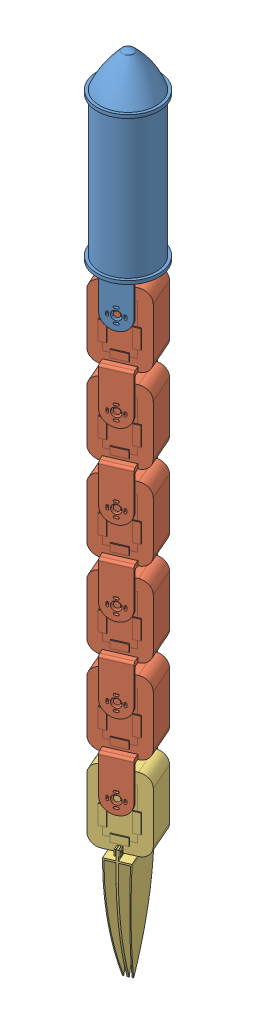
SolidWorks assembly total_final_fish, configuration 預設. Lengths in mm.
Overall size (60.87 716.27 55.2).
7 component instances, 3 part files, 19 mates.
Components (placement in the parent):
- base_link-2: base_link [預設] at (3.3602 198.1192 -73.7093) size (55 204.98 55)
- link2-6: link2 [預設] at (24.2784 37.6563 26.0615) x (0 1 0) z (0.399282 0 0.916828) size (107 45 40.5)
- link2-7: link2 [預設] at (24.2784 -37.0437 26.0615) x (0 1 0) z (0.399282 0 0.916828) size (107 45 40.5)
- link2-8: link2 [預設] at (24.2784 -111.7437 26.0615) x (0 1 0) z (0.399282 0 0.916828) size (107 45 40.5)
- link2-9: link2 [預設] at (24.2784 -186.4437 26.0615) x (0 1 0) z (0.399282 0 0.916828) size (107 45 40.5)
- link2-10: link2 [預設] at (24.2784 -261.1437 26.0615) x (0 1 0) z (0.399282 0 0.916828) size (107 45 40.5)
- link6-2: link6 [預設] at (-11.6105 -236.8157 -14.0084) x (0 1 0) z (0.399282 0 0.916828) size (170.09 49.79 38.13)
Mates (geometry in assembly coordinates):
- 同軸心9: concentric aligned: cylinder of base_link-2 through (17.4906 112.3563 10.4754) axis (-0.399282 0 -0.916828) radius 2.7; cylinder of link2-6 through (18.6885 112.3563 13.2259) axis (-0.399282 0 -0.916828) radius 2.5
- 平行2: parallel aligned: plane of base_link-2 through (5.2908 142.3563 12.5163) normal (-0.916828 0 0.399282); plane of link2-6 through (9.2398 67.6563 47.881) normal (-0.916828 0 0.399282)
- 同軸心10: concentric anti-aligned: cylinder of base_link-2 through (31.6652 112.3563 43.0228) axis (0.399282 0 0.916828) radius 4; cylinder of link2-6 through (31.8648 112.3563 43.4812) axis (-0.399282 0 -0.916828) radius 2.5
- 重合/共線/共點32: coincident aligned: plane of base_link-2 through (30.4673 112.3563 40.2724) normal (-0.399282 0 -0.916828); plane of link2-6 through (30.4673 37.6563 40.2724) normal (-0.399282 0 -0.916828)
- 重合/共線/共點33: coincident aligned: plane of link2-6 through (9.2398 67.6563 47.881) normal (-0.916828 0 0.399282); plane of link2-7 through (9.2398 -7.0437 47.881) normal (-0.916828 0 0.399282)
- 重合/共線/共點34: coincident aligned: plane of link2-6 through (30.4673 37.6563 40.2724) normal (-0.399282 0 -0.916828); plane of link2-7 through (30.4673 -37.0437 40.2724) normal (-0.399282 0 -0.916828)
- 同軸心11: concentric anti-aligned: cylinder of link2-6 through (16.2928 37.6563 7.725) axis (0.399282 0 0.916828) radius 3.7; cylinder of link2-7 through (18.6885 37.6563 13.2259) axis (-0.399282 0 -0.916828) radius 2.5
- 重合/共線/共點35: coincident aligned: plane of link2-7 through (9.2398 -7.0437 47.881) normal (-0.916828 0 0.399282); plane of link2-8 through (9.2398 -81.7437 47.881) normal (-0.916828 0 0.399282)
- 重合/共線/共點36: coincident aligned: plane of link2-7 through (18.6885 52.8909 13.2259) normal (-0.399282 0 -0.916828); plane of link2-8 through (18.6885 -21.8091 13.2259) normal (-0.399282 0 -0.916828)
- 同軸心12: concentric anti-aligned: cylinder of link2-7 through (16.2928 -37.0437 7.725) axis (0.399282 0 0.916828) radius 3.7; cylinder of link2-8 through (18.6885 -37.0437 13.2259) axis (-0.399282 0 -0.916828) radius 2.5
- 重合/共線/共點37: coincident aligned: plane of link2-8 through (9.2398 -81.7437 47.881) normal (-0.916828 0 0.399282); plane of link2-9 through (9.2398 -156.4437 47.881) normal (-0.916828 0 0.399282)
- 重合/共線/共點38: coincident aligned: plane of link2-8 through (18.6885 -21.8091 13.2259) normal (-0.399282 0 -0.916828); plane of link2-9 through (18.6885 -96.5091 13.2259) normal (-0.399282 0 -0.916828)
- 同軸心13: concentric anti-aligned: cylinder of link2-8 through (16.2928 -111.7437 7.725) axis (0.399282 0 0.916828) radius 3.7; cylinder of link2-9 through (18.6885 -111.7437 13.2259) axis (-0.399282 0 -0.916828) radius 2.5
- 重合/共線/共點39: coincident aligned: plane of link2-9 through (9.2398 -156.4437 47.881) normal (-0.916828 0 0.399282); plane of link2-10 through (9.2398 -231.1437 47.881) normal (-0.916828 0 0.399282)
- 同軸心14: concentric anti-aligned: cylinder of link2-9 through (16.2928 -186.4437 7.725) axis (0.399282 0 0.916828) radius 3.7; cylinder of link2-10 through (18.6885 -186.4437 13.2259) axis (-0.399282 0 -0.916828) radius 2.5
- 重合/共線/共點40: coincident aligned: plane of link2-9 through (18.6885 -96.5091 13.2259) normal (-0.399282 0 -0.916828); plane of link2-10 through (18.6885 -171.2091 13.2259) normal (-0.399282 0 -0.916828)
- 重合/共線/共點41: coincident aligned: plane of link2-10 through (9.2398 -231.1437 47.881) normal (-0.916828 0 0.399282); plane of link6-2 through (9.2398 -305.8437 47.881) normal (-0.916828 0 0.399282)
- 重合/共線/共點42: coincident aligned: plane of link2-10 through (18.6885 -171.2091 13.2259) normal (-0.399282 0 -0.916828); plane of link6-2 through (18.6885 -245.9091 13.2259) normal (-0.399282 0 -0.916828)
- 同軸心15: concentric aligned: cylinder of link2-10 through (16.2928 -261.1437 7.725) axis (0.399282 0 0.916828) radius 3.7; cylinder of link6-2 through (16.6921 -261.1437 8.6418) axis (0.399282 0 0.916828) radius 2.5
